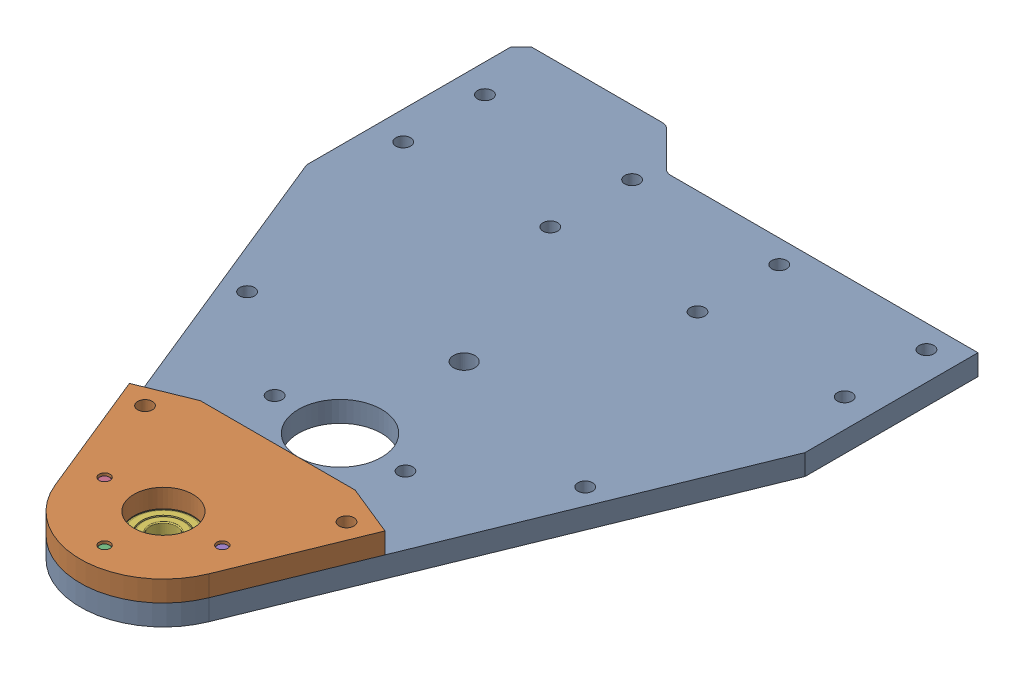
SolidWorks assembly Main Plate Sub Asmbly_1, configuration Default. Lengths in mm.
Overall size (152.4 12.84 210.99).
6 component instances, 4 part files, 0 mates.
Components (placement in the parent):
- Main Plate-1: Main Plate [Default] at origin size (152.4 6.35 210.99)
- Bearing Plate-1: Bearing Plate [Default] at origin size (78.15 6.35 60.33)
- 91294A192 - M4 x 0.7 mm, 12 mm Long Hex Drive Flat Head Screw-1: 91294A192 - M4 x 0.7 mm, 12 mm Long Hex Drive Flat Head Screw [Default] at (0 -33.3375 171.3144) x (1 0 0) z (0 -1 0) size (8 8 12.14)
- 91294A192 - M4 x 0.7 mm, 12 mm Long Hex Drive Flat Head Screw-2: 91294A192 - M4 x 0.7 mm, 12 mm Long Hex Drive Flat Head Screw [Default] at (-18 -33.3375 153.3144) x (1 0 0) z (0 -1 0) size (8 8 12.14)
- 91294A192 - M4 x 0.7 mm, 12 mm Long Hex Drive Flat Head Screw-3: 91294A192 - M4 x 0.7 mm, 12 mm Long Hex Drive Flat Head Screw [Default] at (18 -33.3375 153.3144) x (1 0 0) z (0 -1 0) size (8 8 12.14)
- 8x22x7+Bearing+-+6082Z-8x22x7_6082Z-8x22x7-1: 8x22x7+Bearing+-+6082Z-8x22x7_6082Z-8x22x7 [Default] at (0 -29.8375 153.3144) x (1 0 0) z (0 -1 0) size (22 22 7.01)
